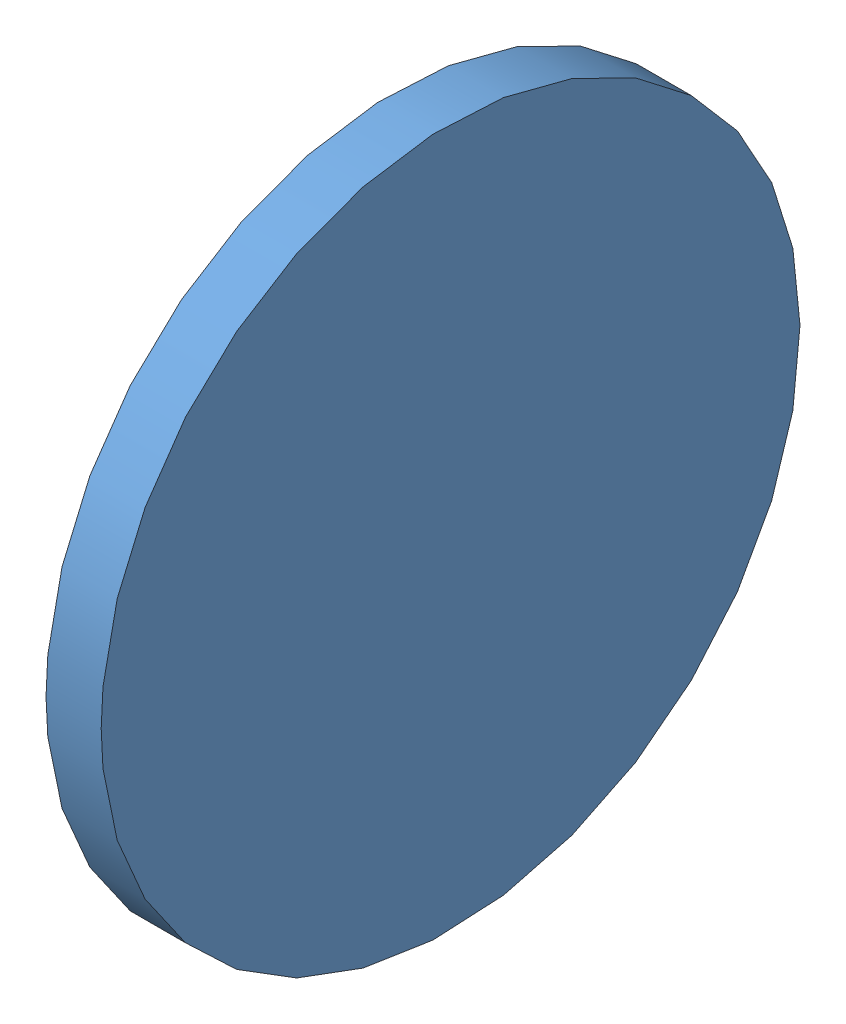
SolidWorks assembly B40-5C(Default-_flexible1), configuration Default. Lengths in mm.
Overall size (54.01 80 87.6).
4 component instances, 3 part files, 0 mates.
Components (placement in the parent):
- A-0027956-1: A-0027956 [Default] at origin size (54.01 80 87.6)
  - A-0027749(Default)-1: A-0027749(Default) [Default] at (0 -40 -30) size (28 80 33)
  - G2314-1-1-1: G2314-1-1 [Default] at (-27 0 26) size (54.01 70 63.21)
- G3002-1: G3002 [Default] at (-22 0 26) x (0 1 0) z (0 0 1) size (19 1.5 19)
